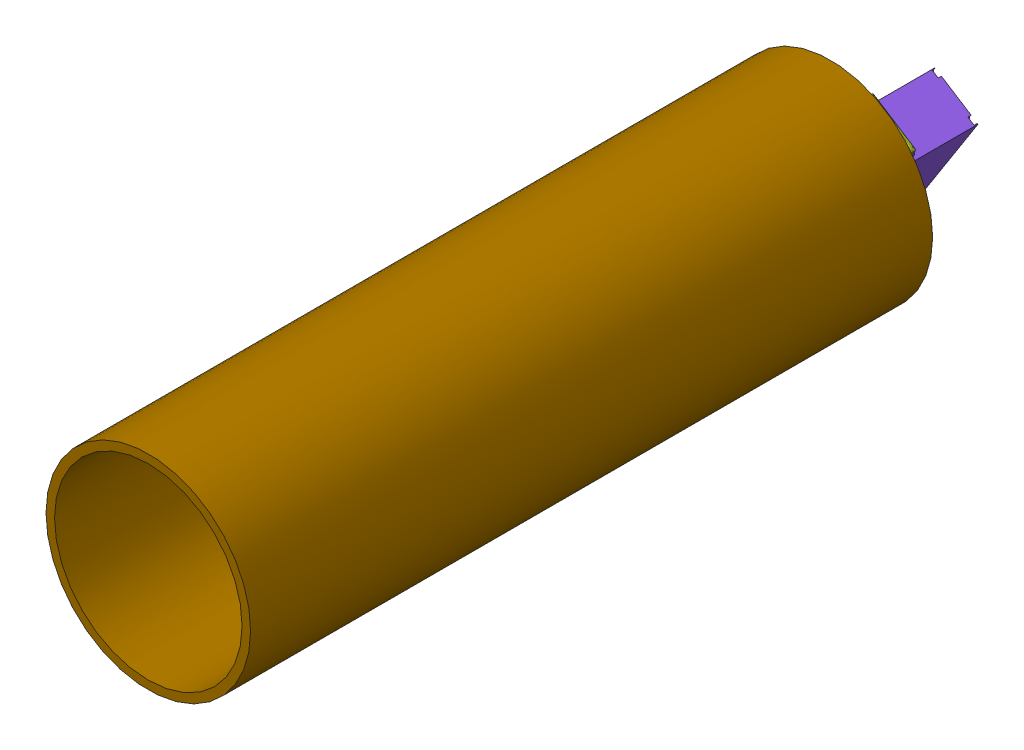
SolidWorks assembly Release Mech, configuration Default. Lengths in mm.
Overall size (109.38 109.38 295.7).
12 component instances, 9 part files, 9 mates.
Components (placement in the parent):
- Capture-1: Capture [Default] at (1.36 24.2904 32.7927) x (-0.675171 -0.737661 0) z (0 0 -1) size (31.46 31.46 19.05)
  - Capture-1: Capture [Default] at origin size (25.4 25.4 19.05)
  - 97493A111_ METRIC PARTIALLY THREADED STUDS-1: 97493A111_ METRIC PARTIALLY THREADED STUDS [97493A111] at (-9.525 0 -13.0175) x (0 -0.924225 -0.381849) z (1 0 0) size (3.47 3.06 6.16)
  - 97493A111_ METRIC PARTIALLY THREADED STUDS-2: 97493A111_ METRIC PARTIALLY THREADED STUDS [97493A111] at (9.525 0 -13.0175) x (0 0.924225 0.381849) z (-1 0 0) size (3.47 3.06 6.16)
  - 9452K720_OIL-RESISTANT BUNA-N MULTIPURPOSE O-RING-1: 9452K720_OIL-RESISTANT BUNA-N MULTIPURPOSE O-RING [9452K72] at (0 0 -16.5989) x (0.645398 -0.763847 0) z (0 0 1) size (22.33 22.33 1.78)
- Torpedo-1: Torpedo [Default] at (-101.9722 -24.2166 227.0636) x (0.230737 0.973016 0) z (0 0 -1) size (90.86 90.86 152.5)
  - Pressure Vessel-1: Pressure Vessel [Default] at (71.0407 89.3516 69.334) size (19.05 19.05 114.3)
  - 8063K170_AIR FILL VALVE-1: 8063K170_AIR FILL VALVE [8063K17] at (71.0407 89.3516 80.4465) x (-0.222419 0.974951 0) z (-0.974951 -0.222419 0) size (14.29 33.45 16.5)
  - Shell-1: Shell [Default] at (71.0407 89.3516 170.934) x (-0.900265 0.435343 0) z (0 0 -1) size (68.03 68.03 152.5)
- Support-1: Support [Default] at (1.36 24.2904 32.7927) x (0.215871 -0.976422 0) z (0 0 -1) size (69.92 69.92 44.45)
- Macro servo2-1: Macro servo2 [Default] at (-9.6017 24.7709 17.8223) x (0.537791 0.843078 0) z (0.843078 -0.537791 0) size (53 44.3 19.65)
- Tube-2: Tube [Default] at (1.36 24.2904 286.7927) size (76.2 76.2 254)
Mates (geometry in assembly coordinates):
- Concentric1: concentric aligned: circle of Torpedo-1/Pressure Vessel-1; cylinder of Capture-1/Capture-1 through (1.36 24.2904 51.8427) axis (0 0 -1) radius 12.7
- Concentric3: concentric aligned: cylinder of Capture-1/Capture-1 through (1.36 24.2904 51.8427) axis (0 0 -1) radius 12.7; cylinder of Macro servo2-1 through (1.36 24.2904 35.3927) axis (0 0 -1) radius 2.8
- Coincident4: coincident aligned: plane of Capture-1/Capture-1 through (1.36 24.2904 32.7927) normal (0 0 -1); plane of Support-1 through (1.36 24.2904 32.7927) normal (0 0 -1)
- Concentric5: concentric aligned: cylinder of Capture-1/Capture-1 through (1.36 24.2904 51.8427) axis (0 0 -1) radius 12.7; cylinder of Support-1 through (1.36 24.2904 64.5427) axis (0 0 -1) radius 18.4977
- Concentric6: concentric anti-aligned: cylinder of Support-1 through (1.36 24.2904 64.5427) axis (0 0 -1) radius 34.925; cylinder of Tube-2 through (1.36 24.2904 32.7927) axis (0 0 1) radius 38.1
- Coincident7: coincident aligned: plane of Support-1 through (1.36 24.2904 32.7927) normal (0 0 -1); plane of Tube-2 through (1.36 24.2904 32.7927) normal (0 0 -1)
- Parallel3: parallel anti-aligned: plane of Torpedo-1/Shell-1 through (2.9101 24.6331 56.1297) normal (0.976422 0.215871 0); plane of Support-1 through (3.8401 24.8387 64.5427) normal (-0.976422 -0.215871 0)
- Coincident9: coincident anti-aligned: plane of Support-1 through (1.36 24.2904 20.0927) normal (0 0 -1); plane of Macro servo2-1 through (-1.3646 37.684 20.0927) normal (0 0 1)
- Perpendicular1: perpendicular: line of Support-1 through (4.2559 46.5416 20.0927) axis (0.843078 -0.537791 0); plane of Macro servo2-1 through (-9.6017 24.7709 17.8223) normal (-0.843078 0.537791 0)
